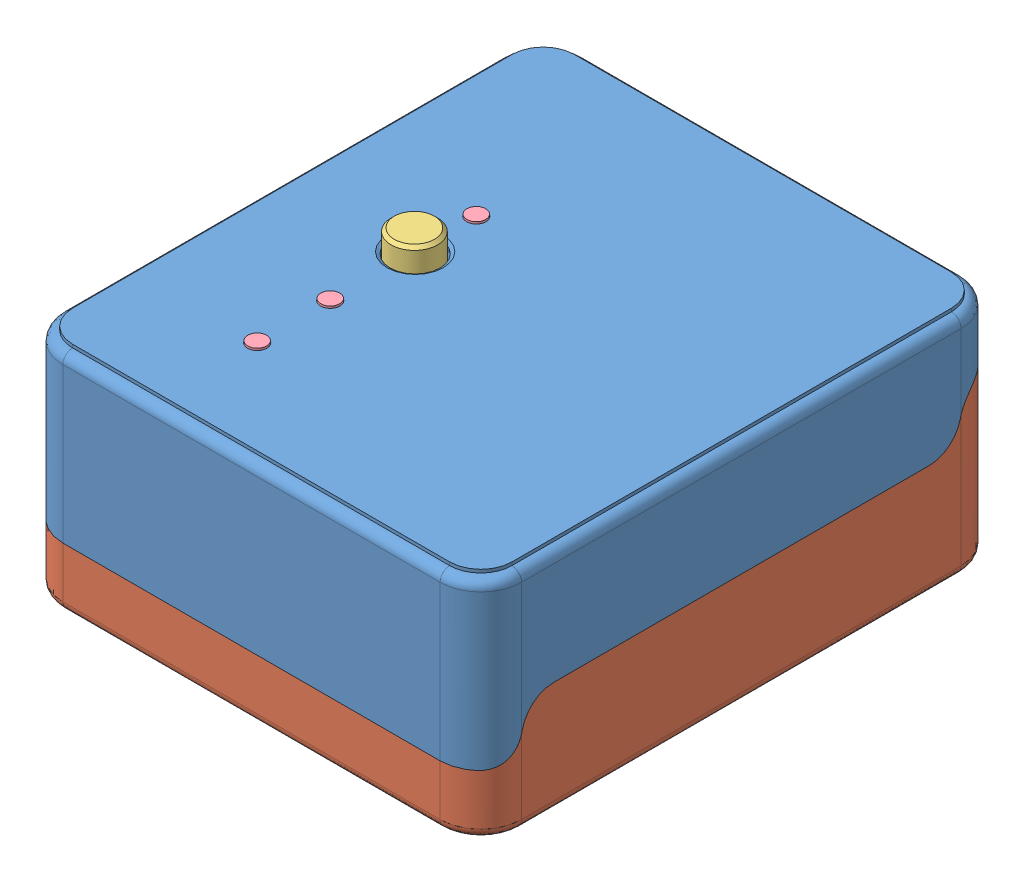
SolidWorks assembly Muscle Mouse v1_1, configuration Default. Lengths in mm.
Overall size (71.44 38.68 81.15).
62 component instances, 14 part files, 176 mates.
Components (placement in the parent):
- Muscle Mouse Board v1.1-1: Muscle Mouse Board v1.1 [Default] at (-18.1857 -3.7277 12.1289) size (55.43 1.85 75.95) (hidden)
- ArduinoMiniPro-1: ArduinoMiniPro [Default] at (-3.4501 0.5723 -8.9143) size (18.31 0.85 33) (hidden)
- BluSmiRF HID-1: BluSmiRF HID [Default] at (-16.9076 0.9474 31.4222) x (0 0 -1) z (1 0 0) size (16.15 3.53 42.04) (hidden)
- Muscle Sensor v3-1: Muscle Sensor v3 [Default] at (-33.1753 0.9474 -13.1715) size (25.4 6.61 28.3) (hidden)
- keystone-PN2479-1: keystone-PN2479 [Default] at (-25.1841 -16.2808 -8.533) x (1 0 0) z (0 0 -1) size (59.43 26.06 37.49) (hidden)
- keystone-PN2479-2: keystone-PN2479 [Default] at (-8.2546 -16.2808 33.121) x (-1 0 0) z (0 0 1) size (59.43 26.06 37.49) (hidden)
- HeaderPin-1: HeaderPin [Default] at (-36.6561 -1.3527 25.0722) x (1 0 0) z (0 0 -1) size (2.5 8.75 2.5) (hidden)
- HeaderPin-2: HeaderPin [Default] at (-36.6561 -1.3527 27.6122) x (1 0 0) z (0 0 -1) size (2.5 8.75 2.5) (hidden)
- HeaderPin-3: HeaderPin [Default] at (-36.6561 -1.3527 30.1522) x (1 0 0) z (0 0 -1) size (2.5 8.75 2.5) (hidden)
- HeaderPin-4: HeaderPin [Default] at (-36.6561 -1.3527 32.6922) x (1 0 0) z (0 0 -1) size (2.5 8.75 2.5) (hidden)
- HeaderPin-5: HeaderPin [Default] at (-36.6561 -1.3527 35.2322) x (1 0 0) z (0 0 -1) size (2.5 8.75 2.5) (hidden)
- HeaderPin-6: HeaderPin [Default] at (-36.6561 -1.3527 37.7722) x (1 0 0) z (0 0 -1) size (2.5 8.75 2.5) (hidden)
- HeaderPin-7: HeaderPin [Default] at (-44.2751 -1.3527 -2.0717) x (1 0 0) z (0 0 -1) size (2.5 8.75 2.5) (hidden)
- HeaderPin-8: HeaderPin [Default] at (-41.7351 -1.3527 -2.0717) x (1 0 0) z (0 0 -1) size (2.5 8.75 2.5) (hidden)
- HeaderPin-9: HeaderPin [Default] at (-39.1951 -1.3527 -2.0717) x (1 0 0) z (0 0 -1) size (2.5 8.75 2.5) (hidden)
- HeaderPin-10: HeaderPin [Default] at (-29.0351 -1.3527 -2.0717) x (1 0 0) z (0 0 -1) size (2.5 8.75 2.5) (hidden)
- HeaderPin-11: HeaderPin [Default] at (-10.8161 -1.3527 -24.1443) x (1 0 0) z (0 0 -1) size (2.5 8.75 2.5) (hidden)
- HeaderPin-12: HeaderPin [Default] at (-31.5751 -1.3527 -2.0717) x (1 0 0) z (0 0 -1) size (2.5 8.75 2.5) (hidden)
- HeaderPin-13: HeaderPin [Default] at (-10.8161 -1.3527 -1.2843) x (1 0 0) z (0 0 -1) size (2.5 8.75 2.5) (hidden)
- HeaderPin-14: HeaderPin [Default] at (-4.7201 -1.3527 6.3357) x (1 0 0) z (0 0 -1) size (2.5 8.75 2.5) (hidden)
- HeaderPin-15: HeaderPin [Default] at (-7.2601 -1.3527 6.3357) x (1 0 0) z (0 0 -1) size (2.5 8.75 2.5) (hidden)
- HeaderPin-16: HeaderPin [Default] at (-2.1801 -1.3527 6.3357) x (1 0 0) z (0 0 -1) size (2.5 8.75 2.5) (hidden)
- HeaderPin-17: HeaderPin [Default] at (3.9159 -1.3527 1.2557) x (1 0 0) z (0 0 -1) size (2.5 8.75 2.5) (hidden)
- HeaderPin-18: HeaderPin [Default] at (3.9159 -1.3527 -6.3643) x (1 0 0) z (0 0 -1) size (2.5 8.75 2.5) (hidden)
- HeaderPin-19: HeaderPin [Default] at (3.9159 -1.3527 -3.8243) x (1 0 0) z (0 0 -1) size (2.5 8.75 2.5) (hidden)
- HeaderPin-20: HeaderPin [Default] at (-10.8161 -1.3527 -8.9043) x (1 0 0) z (0 0 -1) size (2.5 8.75 2.5) (hidden)
- HeaderPin-21: HeaderPin [Default] at (-10.8161 -1.3527 -16.5243) x (1 0 0) z (0 0 -1) size (2.5 8.75 2.5) (hidden)
- HeaderPin-22: HeaderPin [Default] at (-10.8161 -1.3527 -11.4443) x (1 0 0) z (0 0 -1) size (2.5 8.75 2.5) (hidden)
- HeaderPin-23: HeaderPin [Default] at (-10.8161 -1.3527 -13.9843) x (1 0 0) z (0 0 -1) size (2.5 8.75 2.5) (hidden)
- HeaderPin-24: HeaderPin [Default] at (-10.8161 -1.3527 -6.3643) x (1 0 0) z (0 0 -1) size (2.5 8.75 2.5) (hidden)
- HeaderPin-25: HeaderPin [Default] at (-9.8001 -1.3527 6.3357) x (1 0 0) z (0 0 -1) size (2.5 8.75 2.5) (hidden)
- HeaderPin-26: HeaderPin [Default] at (-10.8161 -1.3527 -3.8243) x (1 0 0) z (0 0 -1) size (2.5 8.75 2.5) (hidden)
- HeaderPin-27: HeaderPin [Default] at (-10.8161 -1.3527 -21.6043) x (1 0 0) z (0 0 -1) size (2.5 8.75 2.5) (hidden)
- HeaderPin-28: HeaderPin [Default] at (3.9159 -1.3527 -1.2843) x (1 0 0) z (0 0 -1) size (2.5 8.75 2.5) (hidden)
- HeaderPin-29: HeaderPin [Default] at (-10.8161 -1.3527 1.2557) x (1 0 0) z (0 0 -1) size (2.5 8.75 2.5) (hidden)
- HeaderPin-30: HeaderPin [Default] at (3.9159 -1.3527 3.7957) x (1 0 0) z (0 0 -1) size (2.5 8.75 2.5) (hidden)
- HeaderPin-31: HeaderPin [Default] at (3.9159 -1.3527 -11.4443) x (1 0 0) z (0 0 -1) size (2.5 8.75 2.5) (hidden)
- HeaderPin-32: HeaderPin [Default] at (3.9159 -1.3527 -8.9043) x (1 0 0) z (0 0 -1) size (2.5 8.75 2.5) (hidden)
- HeaderPin-33: HeaderPin [Default] at (3.9159 -1.3527 -13.9843) x (1 0 0) z (0 0 -1) size (2.5 8.75 2.5) (hidden)
- HeaderPin-34: HeaderPin [Default] at (3.9159 -1.3527 -21.6043) x (1 0 0) z (0 0 -1) size (2.5 8.75 2.5) (hidden)
- HeaderPin-35: HeaderPin [Default] at (3.9159 -1.3527 -19.0643) x (1 0 0) z (0 0 -1) size (2.5 8.75 2.5) (hidden)
- HeaderPin-36: HeaderPin [Default] at (3.9159 -1.3527 -16.5243) x (1 0 0) z (0 0 -1) size (2.5 8.75 2.5) (hidden)
- HeaderPin-37: HeaderPin [Default] at (0.3599 -1.3527 6.3357) x (1 0 0) z (0 0 -1) size (2.5 8.75 2.5) (hidden)
- HeaderPin-38: HeaderPin [Default] at (-10.8161 -1.3527 3.7957) x (1 0 0) z (0 0 -1) size (2.5 8.75 2.5) (hidden)
- HeaderPin-39: HeaderPin [Default] at (2.8999 -1.3527 6.3357) x (1 0 0) z (0 0 -1) size (2.5 8.75 2.5) (hidden)
- HeaderPin-40: HeaderPin [Default] at (-10.8161 -1.3527 -19.0643) x (1 0 0) z (0 0 -1) size (2.5 8.75 2.5) (hidden)
- HeaderPin-41: HeaderPin [Default] at (3.9159 -1.3527 -24.1443) x (1 0 0) z (0 0 -1) size (2.5 8.75 2.5) (hidden)
- ClippedPin-1: ClippedPin [Default] at (-44.4402 -1.3527 -24.4618) x (0 0 -1) z (-1 0 0) size (2.5 5.25 2.5) (hidden)
- ClippedPin-2: ClippedPin [Default] at (2.4554 -1.3527 24.7801) x (0 0 -1) z (-1 0 0) size (2.5 5.25 2.5) (hidden)
- ClippedPin-3: ClippedPin [Default] at (2.43 -1.3527 38.0897) x (0 0 -1) z (-1 0 0) size (2.5 5.25 2.5) (hidden)
- ClippedPin-4: ClippedPin [Default] at (-21.8469 -1.3527 -24.4872) x (0 0 -1) z (-1 0 0) size (2.5 5.25 2.5) (hidden)
- PushbuttonBottom-1: PushbuttonBottom [Default] at (-31.9715 -2.2177 12.3106) x (0 0 -1) z (1 0 0) size (9.72 19.93 8.45) (hidden)
- EnclosureTop-1: EnclosureTop [Default] at (-16.7257 13.8198 12.1289) x (-1 0 0) z (0 0 1) size (71.44 26.6 81.15)
- EnclosureBottom-1: EnclosureBottom [Default] at (-16.7257 -21.1802 12.1289) size (71.44 25.43 81.15)
- ButtonCap-1: ButtonCap [Default] at (-31.9965 10.6798 12.0606) size (7.25 6.82 7.25)
- 11mmLightTube-1: 11mmLightTube [Default] at (-31.9053 3.3598 36.6289) size (3.75 11.25 3.75)
- 11mmLightTube-2: 11mmLightTube [Default] at (-31.9053 3.3598 25.2539) size (3.75 11.25 3.75)
- 11mmLightTube-3: 11mmLightTube [Default] at (-31.9053 3.3598 2.5089) size (3.75 11.25 3.75)
- 92010A126-2: 92010A126 [92010A126] at (13.2921 -19.1802 -8.1594) x (-0.055382 0 0.998465) z (0 -1 0) size (5.6 5.6 16.24) (hidden)
- 92010A126-4: 92010A126 [92010A126] at (13.2921 -19.1802 32.4171) x (1 0 0) z (0 -1 0) size (5.6 5.6 16.24) (hidden)
- 92010A126-8: 92010A126 [92010A126] at (-46.7434 -19.1884 12.1289) x (0.93096 0 0.36512) z (0 -1 0) size (5.6 5.6 16.24) (hidden)
- 92010A020-1: 92010A020 [92010A020] at (-16.6663 -6.003 43.1062) x (1 0 0) z (0 -1 0) size (4.7 4.7 10.19) (hidden)
Mates (geometry in assembly coordinates):
- Concentric1: concentric aligned: cylinder of Muscle Mouse Board v1.1-1 through (-36.6561 -4.6027 25.0722) axis (0 1 0) radius 0.508; cylinder of BluSmiRF HID-1 through (-36.6561 0.1473 25.0722) axis (0 1 0) radius 0.508
- Concentric2: concentric aligned: cylinder of Muscle Mouse Board v1.1-1 through (-36.6561 -4.6027 37.7722) axis (0 1 0) radius 0.508; cylinder of BluSmiRF HID-1 through (-36.6561 0.1473 37.7722) axis (0 1 0) radius 0.508
- Concentric3: concentric aligned: cylinder of Muscle Mouse Board v1.1-1 through (6.9512 -4.6027 -18.5182) axis (0 1 0) radius 0.508; cylinder of keystone-PN2479-1 through (6.9512 -11.9073 -18.5182) axis (0 1 0) radius 0.4064
- Concentric4: concentric aligned: cylinder of Muscle Mouse Board v1.1-1 through (6.9512 -4.6027 -5.8182) axis (0 1 0) radius 0.508; cylinder of keystone-PN2479-1 through (6.9512 -11.9073 -5.8182) axis (0 1 0) radius 0.4064
- Concentric5: concentric aligned: cylinder of Muscle Mouse Board v1.1-1 through (-40.3899 -4.6027 43.1062) axis (0 1 0) radius 0.508; cylinder of keystone-PN2479-2 through (-40.3899 -11.9073 43.1062) axis (0 1 0) radius 0.4064
- Concentric6: concentric aligned: cylinder of Muscle Mouse Board v1.1-1 through (-40.3899 -4.6027 30.4062) axis (0 1 0) radius 0.508; cylinder of keystone-PN2479-2 through (-40.3899 -11.9073 30.4062) axis (0 1 0) radius 0.4064
- Concentric7: concentric aligned: cylinder of Muscle Mouse Board v1.1-1 through (-44.2751 -4.6027 -2.0717) axis (0 1 0) radius 0.508; cylinder of Muscle Sensor v3-1 through (-44.2751 0.1473 -2.0717) axis (0 1 0) radius 0.635
- Concentric8: concentric aligned: cylinder of Muscle Mouse Board v1.1-1 through (-29.0351 -4.6027 -2.0717) axis (0 1 0) radius 0.508; cylinder of Muscle Sensor v3-1 through (-29.0351 0.1473 -2.0717) axis (0 1 0) radius 0.635
- Concentric9: concentric aligned: cylinder of Muscle Mouse Board v1.1-1 through (-36.6561 -4.6027 37.7722) axis (0 1 0) radius 0.508; cylinder of HeaderPin-6 through (-36.6561 -5.1027 37.7722) axis (0 1 0) radius 0.4953
- Coincident1: coincident anti-aligned: plane of Muscle Mouse Board v1.1-1 through (9.5293 -2.8527 50.1039) normal (0 1 0); plane of HeaderPin-6 through (-35.4061 -2.8527 36.5222) normal (0 -1 0)
- Coincident2: coincident anti-aligned: plane of BluSmiRF HID-1 through (4.1109 0.1473 23.345) normal (0 -1 0); plane of HeaderPin-6 through (-35.4061 0.1473 36.5222) normal (0 1 0)
- Parallel1: parallel aligned: plane of BluSmiRF HID-1 through (-37.9261 1.7475 39.4994) normal (-1 0 0); plane of HeaderPin-6 through (-37.9061 -2.8527 39.0222) normal (-1 0 0)
- Concentric10: concentric aligned: cylinder of Muscle Mouse Board v1.1-1 through (-36.6561 -4.6027 35.2322) axis (0 1 0) radius 0.508; cylinder of HeaderPin-5 through (-36.6561 -5.1027 35.2322) axis (0 1 0) radius 0.4953
- Concentric11: concentric aligned: cylinder of Muscle Mouse Board v1.1-1 through (-36.6561 -4.6027 32.6922) axis (0 1 0) radius 0.508; cylinder of HeaderPin-4 through (-36.6561 -5.1027 32.6922) axis (0 1 0) radius 0.4953
- Concentric12: concentric aligned: cylinder of Muscle Mouse Board v1.1-1 through (-36.6561 -4.6027 30.1522) axis (0 1 0) radius 0.508; cylinder of HeaderPin-3 through (-36.6561 -5.1027 30.1522) axis (0 1 0) radius 0.4953
- Concentric13: concentric aligned: cylinder of Muscle Mouse Board v1.1-1 through (-36.6561 -4.6027 27.6122) axis (0 1 0) radius 0.508; cylinder of HeaderPin-2 through (-36.6561 -5.1027 27.6122) axis (0 1 0) radius 0.4953
- Concentric14: concentric aligned: cylinder of Muscle Mouse Board v1.1-1 through (-36.6561 -4.6027 25.0722) axis (0 1 0) radius 0.508; cylinder of HeaderPin-1 through (-36.6561 -5.1027 25.0722) axis (0 1 0) radius 0.4953
- Parallel2: parallel aligned: plane of BluSmiRF HID-1 through (-37.9261 1.7475 39.4994) normal (-1 0 0); plane of HeaderPin-5 through (-37.9061 -2.8527 36.4822) normal (-1 0 0)
- Parallel4: parallel aligned: plane of BluSmiRF HID-1 through (-37.9261 1.7475 39.4994) normal (-1 0 0); plane of HeaderPin-4 through (-37.9061 -2.8527 33.9422) normal (-1 0 0)
- Parallel5: parallel aligned: plane of BluSmiRF HID-1 through (-37.9261 1.7475 39.4994) normal (-1 0 0); plane of HeaderPin-3 through (-37.9061 -2.8527 31.4022) normal (-1 0 0)
- Parallel6: parallel aligned: plane of BluSmiRF HID-1 through (-37.9261 1.7475 39.4994) normal (-1 0 0); plane of HeaderPin-2 through (-37.9061 -2.8527 28.8622) normal (-1 0 0)
- Parallel7: parallel aligned: plane of BluSmiRF HID-1 through (-37.9261 1.7475 39.4994) normal (-1 0 0); plane of HeaderPin-1 through (-37.9061 -2.8527 26.3222) normal (-1 0 0)
- Coincident10: coincident anti-aligned: plane of Muscle Mouse Board v1.1-1 through (9.5293 -2.8527 50.1039) normal (0 1 0); plane of HeaderPin-5 through (-35.4061 -2.8527 33.9822) normal (0 -1 0)
- Coincident11: coincident anti-aligned: plane of Muscle Mouse Board v1.1-1 through (9.5293 -2.8527 50.1039) normal (0 1 0); plane of HeaderPin-4 through (-35.4061 -2.8527 31.4422) normal (0 -1 0)
- Coincident12: coincident anti-aligned: plane of Muscle Mouse Board v1.1-1 through (9.5293 -2.8527 50.1039) normal (0 1 0); plane of HeaderPin-3 through (-35.4061 -2.8527 28.9022) normal (0 -1 0)
- Coincident13: coincident anti-aligned: plane of Muscle Mouse Board v1.1-1 through (9.5293 -2.8527 50.1039) normal (0 1 0); plane of HeaderPin-2 through (-35.4061 -2.8527 26.3622) normal (0 -1 0)
- Coincident14: coincident anti-aligned: plane of Muscle Mouse Board v1.1-1 through (9.5293 -2.8527 50.1039) normal (0 1 0); plane of HeaderPin-1 through (-35.4061 -2.8527 23.8222) normal (0 -1 0)
- Concentric15: concentric aligned: cylinder of Muscle Mouse Board v1.1-1 through (-44.2751 -4.6027 -2.0717) axis (0 1 0) radius 0.508; cylinder of HeaderPin-7 through (-44.2751 -5.1027 -2.0717) axis (0 1 0) radius 0.4953
- Concentric16: concentric aligned: cylinder of Muscle Mouse Board v1.1-1 through (-41.7351 -4.6027 -2.0717) axis (0 1 0) radius 0.508; cylinder of HeaderPin-8 through (-41.7351 -5.1027 -2.0717) axis (0 1 0) radius 0.4953
- Concentric17: concentric aligned: cylinder of Muscle Mouse Board v1.1-1 through (-39.1951 -4.6027 -2.0717) axis (0 1 0) radius 0.508; cylinder of HeaderPin-9 through (-39.1951 -5.1027 -2.0717) axis (0 1 0) radius 0.4953
- Concentric18: concentric aligned: cylinder of Muscle Mouse Board v1.1-1 through (-31.5751 -4.6027 -2.0717) axis (0 1 0) radius 0.508; cylinder of HeaderPin-12 through (-31.5751 -5.1027 -2.0717) axis (0 1 0) radius 0.4953
- Concentric19: concentric aligned: cylinder of Muscle Mouse Board v1.1-1 through (-29.0351 -4.6027 -2.0717) axis (0 1 0) radius 0.508; cylinder of HeaderPin-10 through (-29.0351 -5.1027 -2.0717) axis (0 1 0) radius 0.4953
- Coincident15: coincident anti-aligned: plane of Muscle Mouse Board v1.1-1 through (9.5293 -2.8527 50.1039) normal (0 1 0); plane of HeaderPin-7 through (-43.0251 -2.8527 -3.3217) normal (0 -1 0)
- Coincident16: coincident anti-aligned: plane of Muscle Mouse Board v1.1-1 through (9.5293 -2.8527 50.1039) normal (0 1 0); plane of HeaderPin-8 through (-40.4851 -2.8527 -3.3217) normal (0 -1 0)
- Coincident17: coincident anti-aligned: plane of Muscle Mouse Board v1.1-1 through (9.5293 -2.8527 50.1039) normal (0 1 0); plane of HeaderPin-9 through (-37.9451 -2.8527 -3.3217) normal (0 -1 0)
- Coincident18: coincident anti-aligned: plane of Muscle Mouse Board v1.1-1 through (9.5293 -2.8527 50.1039) normal (0 1 0); plane of HeaderPin-12 through (-30.3251 -2.8527 -3.3217) normal (0 -1 0)
- Coincident19: coincident anti-aligned: plane of Muscle Mouse Board v1.1-1 through (9.5293 -2.8527 50.1039) normal (0 1 0); plane of HeaderPin-10 through (-27.7851 -2.8527 -3.3217) normal (0 -1 0)
- Parallel8: parallel aligned: plane of Muscle Mouse Board v1.1-1 through (-45.9007 -2.8527 -25.8461) normal (0 0 -1); plane of HeaderPin-7 through (-45.5251 -2.8527 -3.3217) normal (0 0 -1)
- Parallel9: parallel aligned: plane of Muscle Mouse Board v1.1-1 through (-45.9007 -2.8527 -25.8461) normal (0 0 -1); plane of HeaderPin-8 through (-42.9851 -2.8527 -3.3217) normal (0 0 -1)
- Parallel10: parallel aligned: plane of Muscle Mouse Board v1.1-1 through (-45.9007 -2.8527 -25.8461) normal (0 0 -1); plane of HeaderPin-9 through (-40.4451 -2.8527 -3.3217) normal (0 0 -1)
- Parallel11: parallel aligned: plane of Muscle Mouse Board v1.1-1 through (-45.9007 -2.8527 -25.8461) normal (0 0 -1); plane of HeaderPin-12 through (-32.8251 -2.8527 -3.3217) normal (0 0 -1)
- Parallel12: parallel aligned: plane of Muscle Mouse Board v1.1-1 through (-45.9007 -2.8527 -25.8461) normal (0 0 -1); plane of HeaderPin-10 through (-30.2851 -2.8527 -3.3217) normal (0 0 -1)
- Coincident25: coincident anti-aligned: plane of Muscle Sensor v3-1 through (-45.8753 0.1473 -0.4715) normal (0 -1 0); plane of HeaderPin-7 through (-43.0251 0.1473 -3.3217) normal (0 1 0)
- Concentric20: concentric anti-aligned: cylinder of Muscle Mouse Board v1.1-1 through (-10.8161 -4.6027 -24.1443) axis (0 1 0) radius 0.508; cylinder of ArduinoMiniPro-1 through (-10.8161 0.9973 -24.1443) axis (0 -1 0) radius 0.508
- Concentric22: concentric anti-aligned: cylinder of Muscle Mouse Board v1.1-1 through (3.9159 -4.6027 3.7957) axis (0 1 0) radius 0.508; cylinder of ArduinoMiniPro-1 through (3.9159 0.9973 3.7957) axis (0 -1 0) radius 0.508
- Concentric23: concentric aligned: cylinder of Muscle Mouse Board v1.1-1 through (3.9159 -4.6027 -24.1443) axis (0 1 0) radius 0.508; cylinder of HeaderPin-41 through (3.9159 -5.1027 -24.1443) axis (0 1 0) radius 0.4953
- Concentric24: concentric aligned: cylinder of Muscle Mouse Board v1.1-1 through (3.9159 -4.6027 -21.6043) axis (0 1 0) radius 0.508; cylinder of HeaderPin-34 through (3.9159 -5.1027 -21.6043) axis (0 1 0) radius 0.4953
- Concentric25: concentric aligned: cylinder of Muscle Mouse Board v1.1-1 through (3.9159 -4.6027 -19.0643) axis (0 1 0) radius 0.508; cylinder of HeaderPin-35 through (3.9159 -5.1027 -19.0643) axis (0 1 0) radius 0.4953
- Concentric26: concentric aligned: cylinder of Muscle Mouse Board v1.1-1 through (3.9159 -4.6027 -16.5243) axis (0 1 0) radius 0.508; cylinder of HeaderPin-36 through (3.9159 -5.1027 -16.5243) axis (0 1 0) radius 0.4953
- Concentric27: concentric aligned: cylinder of Muscle Mouse Board v1.1-1 through (3.9159 -4.6027 -13.9843) axis (0 1 0) radius 0.508; cylinder of HeaderPin-33 through (3.9159 -5.1027 -13.9843) axis (0 1 0) radius 0.4953
- Concentric28: concentric aligned: cylinder of Muscle Mouse Board v1.1-1 through (3.9159 -4.6027 -11.4443) axis (0 1 0) radius 0.508; cylinder of HeaderPin-31 through (3.9159 -5.1027 -11.4443) axis (0 1 0) radius 0.4953
- Concentric30: concentric aligned: cylinder of Muscle Mouse Board v1.1-1 through (3.9159 -4.6027 -8.9043) axis (0 1 0) radius 0.508; cylinder of HeaderPin-32 through (3.9159 -5.1027 -8.9043) axis (0 1 0) radius 0.4953
- Concentric31: concentric aligned: cylinder of Muscle Mouse Board v1.1-1 through (3.9159 -4.6027 -6.3643) axis (0 1 0) radius 0.508; cylinder of HeaderPin-18 through (3.9159 -5.1027 -6.3643) axis (0 1 0) radius 0.4953
- Concentric32: concentric aligned: cylinder of Muscle Mouse Board v1.1-1 through (3.9159 -4.6027 3.7957) axis (0 1 0) radius 0.508; cylinder of HeaderPin-30 through (3.9159 -5.1027 3.7957) axis (0 1 0) radius 0.4953
- Concentric33: concentric aligned: cylinder of Muscle Mouse Board v1.1-1 through (3.9159 -4.6027 1.2557) axis (0 1 0) radius 0.508; cylinder of HeaderPin-17 through (3.9159 -5.1027 1.2557) axis (0 1 0) radius 0.4953
- Concentric34: concentric aligned: cylinder of Muscle Mouse Board v1.1-1 through (3.9159 -4.6027 -1.2843) axis (0 1 0) radius 0.508; cylinder of HeaderPin-28 through (3.9159 -5.1027 -1.2843) axis (0 1 0) radius 0.4953
- Concentric35: concentric aligned: cylinder of Muscle Mouse Board v1.1-1 through (3.9159 -4.6027 -3.8243) axis (0 1 0) radius 0.508; cylinder of HeaderPin-19 through (3.9159 -5.1027 -3.8243) axis (0 1 0) radius 0.4953
- Concentric36: concentric aligned: cylinder of Muscle Mouse Board v1.1-1 through (2.8999 -4.6027 6.3357) axis (0 1 0) radius 0.508; cylinder of HeaderPin-39 through (2.8999 -5.1027 6.3357) axis (0 1 0) radius 0.4953
- Parallel13: parallel aligned: plane of Muscle Mouse Board v1.1-1 through (9.5293 -2.8527 -25.8461) normal (1 0 0); plane of HeaderPin-30 through (5.1659 -2.8527 5.0457) normal (1 0 0)
- Parallel14: parallel aligned: plane of Muscle Mouse Board v1.1-1 through (9.5293 -2.8527 -25.8461) normal (1 0 0); plane of HeaderPin-17 through (5.1659 -2.8527 2.5057) normal (1 0 0)
- Parallel15: parallel aligned: plane of Muscle Mouse Board v1.1-1 through (9.5293 -2.8527 -25.8461) normal (1 0 0); plane of HeaderPin-28 through (5.1659 -2.8527 -0.0343) normal (1 0 0)
- Parallel16: parallel aligned: plane of Muscle Mouse Board v1.1-1 through (9.5293 -2.8527 -25.8461) normal (1 0 0); plane of HeaderPin-19 through (5.1659 -2.8527 -2.5743) normal (1 0 0)
- Parallel17: parallel aligned: plane of Muscle Mouse Board v1.1-1 through (9.5293 -2.8527 -25.8461) normal (1 0 0); plane of HeaderPin-18 through (5.1659 -2.8527 -5.1143) normal (1 0 0)
- Parallel18: parallel aligned: plane of Muscle Mouse Board v1.1-1 through (9.5293 -2.8527 -25.8461) normal (1 0 0); plane of HeaderPin-32 through (5.1659 -2.8527 -7.6543) normal (1 0 0)
- Parallel19: parallel aligned: plane of Muscle Mouse Board v1.1-1 through (9.5293 -2.8527 -25.8461) normal (1 0 0); plane of HeaderPin-31 through (5.1659 -2.8527 -10.1943) normal (1 0 0)
- Parallel20: parallel aligned: plane of Muscle Mouse Board v1.1-1 through (9.5293 -2.8527 -25.8461) normal (1 0 0); plane of HeaderPin-33 through (5.1659 -2.8527 -12.7343) normal (1 0 0)
- Parallel21: parallel aligned: plane of Muscle Mouse Board v1.1-1 through (9.5293 -2.8527 -25.8461) normal (1 0 0); plane of HeaderPin-36 through (5.1659 -2.8527 -15.2743) normal (1 0 0)
- Parallel22: parallel aligned: plane of Muscle Mouse Board v1.1-1 through (9.5293 -2.8527 -25.8461) normal (1 0 0); plane of HeaderPin-35 through (5.1659 -2.8527 -17.8143) normal (1 0 0)
- Parallel23: parallel aligned: plane of Muscle Mouse Board v1.1-1 through (9.5293 -2.8527 -25.8461) normal (1 0 0); plane of HeaderPin-34 through (5.1659 -2.8527 -20.3543) normal (1 0 0)
- Parallel24: parallel aligned: plane of Muscle Mouse Board v1.1-1 through (9.5293 -2.8527 -25.8461) normal (1 0 0); plane of HeaderPin-41 through (5.1659 -2.8527 -22.8943) normal (1 0 0)
- Coincident38: coincident anti-aligned: plane of Muscle Mouse Board v1.1-1 through (9.5293 -2.8527 50.1039) normal (0 1 0); plane of HeaderPin-39 through (4.1499 -2.8527 5.0857) normal (0 -1 0)
- Coincident39: coincident anti-aligned: plane of Muscle Mouse Board v1.1-1 through (9.5293 -2.8527 50.1039) normal (0 1 0); plane of HeaderPin-30 through (5.1659 -2.8527 2.5457) normal (0 -1 0)
- Coincident40: coincident anti-aligned: plane of Muscle Mouse Board v1.1-1 through (9.5293 -2.8527 50.1039) normal (0 1 0); plane of HeaderPin-28 through (5.1659 -2.8527 -2.5343) normal (0 -1 0)
- Coincident41: coincident anti-aligned: plane of Muscle Mouse Board v1.1-1 through (9.5293 -2.8527 50.1039) normal (0 1 0); plane of HeaderPin-17 through (5.1659 -2.8527 0.0057) normal (0 -1 0)
- Coincident42: coincident anti-aligned: plane of Muscle Mouse Board v1.1-1 through (9.5293 -2.8527 50.1039) normal (0 1 0); plane of HeaderPin-19 through (5.1659 -2.8527 -5.0743) normal (0 -1 0)
- Coincident43: coincident anti-aligned: plane of Muscle Mouse Board v1.1-1 through (9.5293 -2.8527 50.1039) normal (0 1 0); plane of HeaderPin-18 through (5.1659 -2.8527 -7.6143) normal (0 -1 0)
- Coincident44: coincident anti-aligned: plane of Muscle Mouse Board v1.1-1 through (9.5293 -2.8527 50.1039) normal (0 1 0); plane of HeaderPin-32 through (5.1659 -2.8527 -10.1543) normal (0 -1 0)
- Coincident45: coincident anti-aligned: plane of Muscle Mouse Board v1.1-1 through (9.5293 -2.8527 50.1039) normal (0 1 0); plane of HeaderPin-31 through (5.1659 -2.8527 -12.6943) normal (0 -1 0)
- Coincident46: coincident anti-aligned: plane of Muscle Mouse Board v1.1-1 through (9.5293 -2.8527 50.1039) normal (0 1 0); plane of HeaderPin-33 through (5.1659 -2.8527 -15.2343) normal (0 -1 0)
- Coincident47: coincident anti-aligned: plane of Muscle Mouse Board v1.1-1 through (9.5293 -2.8527 50.1039) normal (0 1 0); plane of HeaderPin-36 through (5.1659 -2.8527 -17.7743) normal (0 -1 0)
- Coincident48: coincident anti-aligned: plane of Muscle Mouse Board v1.1-1 through (9.5293 -2.8527 50.1039) normal (0 1 0); plane of HeaderPin-35 through (5.1659 -2.8527 -20.3143) normal (0 -1 0)
- Coincident49: coincident anti-aligned: plane of Muscle Mouse Board v1.1-1 through (9.5293 -2.8527 50.1039) normal (0 1 0); plane of HeaderPin-34 through (5.1659 -2.8527 -22.8543) normal (0 -1 0)
- Coincident50: coincident anti-aligned: plane of Muscle Mouse Board v1.1-1 through (9.5293 -2.8527 50.1039) normal (0 1 0); plane of HeaderPin-41 through (5.1659 -2.8527 -25.3943) normal (0 -1 0)
- Concentric37: concentric aligned: cylinder of Muscle Mouse Board v1.1-1 through (0.3599 -4.6027 6.3357) axis (0 1 0) radius 0.508; cylinder of HeaderPin-37 through (0.3599 -5.1027 6.3357) axis (0 1 0) radius 0.4953
- Concentric39: concentric aligned: cylinder of Muscle Mouse Board v1.1-1 through (-4.7201 -4.6027 6.3357) axis (0 1 0) radius 0.508; cylinder of HeaderPin-14 through (-4.7201 -5.1027 6.3357) axis (0 1 0) radius 0.4953
- Concentric40: concentric aligned: cylinder of Muscle Mouse Board v1.1-1 through (-2.1801 -4.6027 6.3357) axis (0 1 0) radius 0.508; cylinder of HeaderPin-16 through (-2.1801 -5.1027 6.3357) axis (0 1 0) radius 0.4953
- Concentric41: concentric aligned: cylinder of Muscle Mouse Board v1.1-1 through (-7.2601 -4.6027 6.3357) axis (0 1 0) radius 0.508; cylinder of HeaderPin-15 through (-7.2601 -5.1027 6.3357) axis (0 1 0) radius 0.4953
- Concentric42: concentric aligned: cylinder of Muscle Mouse Board v1.1-1 through (-9.8001 -4.6027 6.3357) axis (0 1 0) radius 0.508; cylinder of HeaderPin-25 through (-9.8001 -5.1027 6.3357) axis (0 1 0) radius 0.4953
- Parallel25: parallel aligned: plane of Muscle Mouse Board v1.1-1 through (9.5293 -2.8527 50.1039) normal (0 0 1); plane of HeaderPin-25 through (-11.0501 -2.8527 7.5857) normal (0 0 1)
- Parallel26: parallel aligned: plane of Muscle Mouse Board v1.1-1 through (9.5293 -2.8527 50.1039) normal (0 0 1); plane of HeaderPin-15 through (-8.5101 -2.8527 7.5857) normal (0 0 1)
- Parallel27: parallel aligned: plane of Muscle Mouse Board v1.1-1 through (9.5293 -2.8527 50.1039) normal (0 0 1); plane of HeaderPin-14 through (-5.9701 -2.8527 7.5857) normal (0 0 1)
- Parallel28: parallel aligned: plane of Muscle Mouse Board v1.1-1 through (9.5293 -2.8527 50.1039) normal (0 0 1); plane of HeaderPin-16 through (-3.4301 -2.8527 7.5857) normal (0 0 1)
- Parallel29: parallel aligned: plane of Muscle Mouse Board v1.1-1 through (9.5293 -2.8527 50.1039) normal (0 0 1); plane of HeaderPin-38 through (-12.0661 -2.8527 5.0457) normal (0 0 1)
- Coincident56: coincident anti-aligned: plane of Muscle Mouse Board v1.1-1 through (9.5293 -2.8527 50.1039) normal (0 1 0); plane of HeaderPin-37 through (1.6099 -2.8527 5.0857) normal (0 -1 0)
- Coincident57: coincident anti-aligned: plane of Muscle Mouse Board v1.1-1 through (9.5293 -2.8527 50.1039) normal (0 1 0); plane of HeaderPin-16 through (-0.9301 -2.8527 5.0857) normal (0 -1 0)
- Coincident58: coincident anti-aligned: plane of Muscle Mouse Board v1.1-1 through (9.5293 -2.8527 50.1039) normal (0 1 0); plane of HeaderPin-14 through (-3.4701 -2.8527 5.0857) normal (0 -1 0)
- Coincident59: coincident anti-aligned: plane of Muscle Mouse Board v1.1-1 through (9.5293 -2.8527 50.1039) normal (0 1 0); plane of HeaderPin-25 through (-8.5501 -2.8527 5.0857) normal (0 -1 0)
- Coincident60: coincident anti-aligned: plane of Muscle Mouse Board v1.1-1 through (9.5293 -2.8527 50.1039) normal (0 1 0); plane of HeaderPin-15 through (-6.0101 -2.8527 5.0857) normal (0 -1 0)
- Concentric43: concentric aligned: cylinder of Muscle Mouse Board v1.1-1 through (-10.8161 -4.6027 3.7957) axis (0 1 0) radius 0.508; cylinder of HeaderPin-38 through (-10.8161 -5.1027 3.7957) axis (0 1 0) radius 0.4953
- Concentric44: concentric aligned: cylinder of HeaderPin-29 through (-10.8161 -5.1027 1.2557) axis (0 1 0) radius 0.4953; cylinder of Muscle Mouse Board v1.1-1 through (-10.8161 -4.6027 1.2557) axis (0 1 0) radius 0.508
- Concentric45: concentric aligned: cylinder of Muscle Mouse Board v1.1-1 through (-10.8161 -4.6027 -1.2843) axis (0 1 0) radius 0.508; cylinder of HeaderPin-13 through (-10.8161 -5.1027 -1.2843) axis (0 1 0) radius 0.4953
- Concentric46: concentric aligned: cylinder of Muscle Mouse Board v1.1-1 through (-10.8161 -4.6027 -3.8243) axis (0 1 0) radius 0.508; cylinder of HeaderPin-26 through (-10.8161 -5.1027 -3.8243) axis (0 1 0) radius 0.4953
- Concentric47: concentric aligned: cylinder of Muscle Mouse Board v1.1-1 through (-10.8161 -4.6027 -6.3643) axis (0 1 0) radius 0.508; cylinder of HeaderPin-24 through (-10.8161 -5.1027 -6.3643) axis (0 1 0) radius 0.4953
- Concentric48: concentric aligned: cylinder of Muscle Mouse Board v1.1-1 through (-10.8161 -4.6027 -8.9043) axis (0 1 0) radius 0.508; cylinder of HeaderPin-20 through (-10.8161 -5.1027 -8.9043) axis (0 1 0) radius 0.4953
- Concentric49: concentric aligned: cylinder of Muscle Mouse Board v1.1-1 through (-10.8161 -4.6027 -24.1443) axis (0 1 0) radius 0.508; cylinder of HeaderPin-11 through (-10.8161 -5.1027 -24.1443) axis (0 1 0) radius 0.4953
- Concentric50: concentric aligned: cylinder of Muscle Mouse Board v1.1-1 through (-10.8161 -4.6027 -21.6043) axis (0 1 0) radius 0.508; cylinder of HeaderPin-27 through (-10.8161 -5.1027 -21.6043) axis (0 1 0) radius 0.4953
- Concentric51: concentric aligned: cylinder of Muscle Mouse Board v1.1-1 through (-10.8161 -4.6027 -19.0643) axis (0 1 0) radius 0.508; cylinder of HeaderPin-40 through (-10.8161 -5.1027 -19.0643) axis (0 1 0) radius 0.4953
- Concentric52: concentric aligned: cylinder of Muscle Mouse Board v1.1-1 through (-10.8161 -4.6027 -16.5243) axis (0 1 0) radius 0.508; cylinder of HeaderPin-21 through (-10.8161 -5.1027 -16.5243) axis (0 1 0) radius 0.4953
- Concentric53: concentric aligned: cylinder of Muscle Mouse Board v1.1-1 through (-10.8161 -4.6027 -11.4443) axis (0 1 0) radius 0.508; cylinder of HeaderPin-22 through (-10.8161 -5.1027 -11.4443) axis (0 1 0) radius 0.4953
- Concentric54: concentric aligned: cylinder of Muscle Mouse Board v1.1-1 through (-10.8161 -4.6027 -13.9843) axis (0 1 0) radius 0.508; cylinder of HeaderPin-23 through (-10.8161 -5.1027 -13.9843) axis (0 1 0) radius 0.4953
- Parallel30: parallel aligned: plane of Muscle Mouse Board v1.1-1 through (-45.9007 -2.8527 1.0539) normal (-1 0 0); plane of HeaderPin-11 through (-12.0661 -2.8527 -22.8943) normal (-1 0 0)
- Parallel31: parallel aligned: plane of Muscle Mouse Board v1.1-1 through (-45.9007 -2.8527 1.0539) normal (-1 0 0); plane of HeaderPin-27 through (-12.0661 -2.8527 -20.3543) normal (-1 0 0)
- Parallel32: parallel aligned: plane of Muscle Mouse Board v1.1-1 through (-45.9007 -2.8527 1.0539) normal (-1 0 0); plane of HeaderPin-40 through (-12.0661 -2.8527 -17.8143) normal (-1 0 0)
- Parallel33: parallel aligned: plane of Muscle Mouse Board v1.1-1 through (-45.9007 -2.8527 1.0539) normal (-1 0 0); plane of HeaderPin-21 through (-12.0661 -2.8527 -15.2743) normal (-1 0 0)
- Parallel34: parallel aligned: plane of Muscle Mouse Board v1.1-1 through (-45.9007 -2.8527 1.0539) normal (-1 0 0); plane of HeaderPin-23 through (-12.0661 -2.8527 -12.7343) normal (-1 0 0)
- Parallel35: parallel aligned: plane of Muscle Mouse Board v1.1-1 through (-45.9007 -2.8527 1.0539) normal (-1 0 0); plane of HeaderPin-22 through (-12.0661 -2.8527 -10.1943) normal (-1 0 0)
- Parallel36: parallel aligned: plane of Muscle Mouse Board v1.1-1 through (-45.9007 -2.8527 1.0539) normal (-1 0 0); plane of HeaderPin-20 through (-12.0661 -2.8527 -7.6543) normal (-1 0 0)
- Parallel37: parallel aligned: plane of Muscle Mouse Board v1.1-1 through (-45.9007 -2.8527 1.0539) normal (-1 0 0); plane of HeaderPin-24 through (-12.0661 -2.8527 -5.1143) normal (-1 0 0)
- Parallel38: parallel aligned: plane of Muscle Mouse Board v1.1-1 through (-45.9007 -2.8527 1.0539) normal (-1 0 0); plane of HeaderPin-26 through (-12.0661 -2.8527 -2.5743) normal (-1 0 0)
- Parallel39: parallel aligned: plane of Muscle Mouse Board v1.1-1 through (-45.9007 -2.8527 1.0539) normal (-1 0 0); plane of HeaderPin-13 through (-12.0661 -2.8527 -0.0343) normal (-1 0 0)
- Parallel40: parallel aligned: plane of Muscle Mouse Board v1.1-1 through (-45.9007 -2.8527 1.0539) normal (-1 0 0); plane of HeaderPin-29 through (-12.0661 -2.8527 2.5057) normal (-1 0 0)
- Parallel41: parallel aligned: plane of Muscle Mouse Board v1.1-1 through (-45.9007 -2.8527 1.0539) normal (-1 0 0); plane of HeaderPin-38 through (-12.0661 -2.8527 5.0457) normal (-1 0 0)
- Coincident73: coincident anti-aligned: plane of Muscle Mouse Board v1.1-1 through (9.5293 -2.8527 50.1039) normal (0 1 0); plane of HeaderPin-11 through (-9.5661 -2.8527 -25.3943) normal (0 -1 0)
- Coincident74: coincident anti-aligned: plane of Muscle Mouse Board v1.1-1 through (9.5293 -2.8527 50.1039) normal (0 1 0); plane of HeaderPin-27 through (-9.5661 -2.8527 -22.8543) normal (0 -1 0)
- Coincident75: coincident anti-aligned: plane of Muscle Mouse Board v1.1-1 through (9.5293 -2.8527 50.1039) normal (0 1 0); plane of HeaderPin-40 through (-9.5661 -2.8527 -20.3143) normal (0 -1 0)
- Coincident76: coincident anti-aligned: plane of Muscle Mouse Board v1.1-1 through (9.5293 -2.8527 50.1039) normal (0 1 0); plane of HeaderPin-21 through (-9.5661 -2.8527 -17.7743) normal (0 -1 0)
- Coincident77: coincident anti-aligned: plane of Muscle Mouse Board v1.1-1 through (9.5293 -2.8527 50.1039) normal (0 1 0); plane of HeaderPin-23 through (-9.5661 -2.8527 -15.2343) normal (0 -1 0)
- Coincident78: coincident anti-aligned: plane of Muscle Mouse Board v1.1-1 through (9.5293 -2.8527 50.1039) normal (0 1 0); plane of HeaderPin-22 through (-9.5661 -2.8527 -12.6943) normal (0 -1 0)
- Coincident79: coincident anti-aligned: plane of Muscle Mouse Board v1.1-1 through (9.5293 -2.8527 50.1039) normal (0 1 0); plane of HeaderPin-20 through (-9.5661 -2.8527 -10.1543) normal (0 -1 0)
- Coincident80: coincident anti-aligned: plane of Muscle Mouse Board v1.1-1 through (9.5293 -2.8527 50.1039) normal (0 1 0); plane of HeaderPin-24 through (-9.5661 -2.8527 -7.6143) normal (0 -1 0)
- Coincident81: coincident anti-aligned: plane of Muscle Mouse Board v1.1-1 through (9.5293 -2.8527 50.1039) normal (0 1 0); plane of HeaderPin-26 through (-9.5661 -2.8527 -5.0743) normal (0 -1 0)
- Coincident82: coincident anti-aligned: plane of Muscle Mouse Board v1.1-1 through (9.5293 -2.8527 50.1039) normal (0 1 0); plane of HeaderPin-38 through (-9.5661 -2.8527 2.5457) normal (0 -1 0)
- Coincident83: coincident anti-aligned: plane of Muscle Mouse Board v1.1-1 through (9.5293 -2.8527 50.1039) normal (0 1 0); plane of HeaderPin-13 through (-9.5661 -2.8527 -2.5343) normal (0 -1 0)
- Coincident84: coincident anti-aligned: plane of Muscle Mouse Board v1.1-1 through (9.5293 -2.8527 50.1039) normal (0 1 0); plane of HeaderPin-29 through (-9.5661 -2.8527 0.0057) normal (0 -1 0)
- Coincident85: coincident anti-aligned: plane of ArduinoMiniPro-1 through (5.7066 0.1473 7.5857) normal (0 -1 0); plane of HeaderPin-11 through (-9.5661 0.1473 -25.3943) normal (0 1 0)
- Concentric55: concentric aligned: cylinder of Muscle Mouse Board v1.1-1 through (-44.4402 -4.6027 -24.4618) axis (0 1 0) radius 0.508; cylinder of ClippedPin-1 through (-44.4402 -5.1027 -24.4618) axis (0 1 0) radius 0.4953
- Concentric56: concentric aligned: cylinder of Muscle Mouse Board v1.1-1 through (-21.8469 -4.6027 -24.4872) axis (0 1 0) radius 0.508; cylinder of ClippedPin-4 through (-21.8469 -5.1027 -24.4872) axis (0 1 0) radius 0.4953
- Concentric57: concentric aligned: cylinder of Muscle Mouse Board v1.1-1 through (2.43 -4.6027 38.0897) axis (0 1 0) radius 0.508; cylinder of ClippedPin-3 through (2.43 -5.1027 38.0897) axis (0 1 0) radius 0.4953
- Concentric58: concentric aligned: cylinder of Muscle Mouse Board v1.1-1 through (2.4554 -4.6027 24.7801) axis (0 1 0) radius 0.508; cylinder of ClippedPin-2 through (2.4554 -5.1027 24.7801) axis (0 1 0) radius 0.4953
- Coincident86: coincident anti-aligned: plane of Muscle Mouse Board v1.1-1 through (9.5293 -2.8527 50.1039) normal (0 1 0); plane of ClippedPin-1 through (-45.6902 -2.8527 -25.7118) normal (0 -1 0)
- Coincident87: coincident anti-aligned: plane of Muscle Mouse Board v1.1-1 through (9.5293 -2.8527 50.1039) normal (0 1 0); plane of ClippedPin-4 through (-23.0969 -2.8527 -25.7372) normal (0 -1 0)
- Coincident88: coincident anti-aligned: plane of Muscle Mouse Board v1.1-1 through (9.5293 -2.8527 50.1039) normal (0 1 0); plane of ClippedPin-3 through (1.18 -2.8527 36.8397) normal (0 -1 0)
- Coincident89: coincident anti-aligned: plane of Muscle Mouse Board v1.1-1 through (9.5293 -2.8527 50.1039) normal (0 1 0); plane of ClippedPin-2 through (1.2054 -2.8527 23.5301) normal (0 -1 0)
- Parallel42: parallel aligned: plane of Muscle Mouse Board v1.1-1 through (9.5293 -2.8527 -25.8461) normal (1 0 0); plane of ClippedPin-3 through (3.68 -2.8527 39.3397) normal (1 0 0)
- Parallel43: parallel aligned: plane of Muscle Mouse Board v1.1-1 through (9.5293 -2.8527 -25.8461) normal (1 0 0); plane of ClippedPin-2 through (3.7054 -2.8527 26.0301) normal (1 0 0)
- Parallel44: parallel aligned: plane of Muscle Mouse Board v1.1-1 through (-45.9007 -2.8527 -25.8461) normal (0 0 -1); plane of ClippedPin-1 through (-43.1902 -2.8527 -25.7118) normal (0 0 -1)
- Parallel45: parallel aligned: plane of Muscle Mouse Board v1.1-1 through (-45.9007 -2.8527 -25.8461) normal (0 0 -1); plane of ClippedPin-4 through (-20.5969 -2.8527 -25.7372) normal (0 0 -1)
- Coincident90: coincident anti-aligned: plane of Muscle Mouse Board v1.1-1 through (9.5293 -2.8527 50.1039) normal (0 1 0); plane of PushbuttonBottom-1 through (-40.5022 -2.8527 16.6603) normal (0 -1 0)
- Parallel47: parallel anti-aligned: plane of Muscle Mouse Board v1.1-1 through (9.5293 -2.8527 50.1039) normal (0 1 0); plane of EnclosureTop-1 through (-52.4444 12.3198 52.7054) normal (0 -1 0)
- Coincident93: coincident aligned: plane of Muscle Mouse Board v1.1-1 through (-16.7257 -3.7277 12.1289) normal (-1 0 0); plane of EnclosureTop-1
- Coincident96: coincident aligned: plane of Muscle Mouse Board v1.1-1 through (-18.1857 -3.7277 12.1289) normal (0 0 -1); plane of EnclosureTop-1 through (-16.7257 13.8198 12.1289) normal (0 0 -1)
- Coincident98: coincident aligned: plane of Muscle Mouse Board v1.1-1 through (-18.1857 -3.7277 12.1289) normal (0 0 -1); plane of EnclosureBottom-1 through (-16.7257 -21.1802 12.1289) normal (0 0 -1)
- Coincident99: coincident anti-aligned: plane of Muscle Mouse Board v1.1-1 through (-16.7257 -3.7277 12.1289) normal (-1 0 0); plane of EnclosureBottom-1 through (-16.7257 -21.1802 12.1289) normal (1 0 0)
- Parallel48: parallel anti-aligned: plane of PushbuttonBottom-1 through (-30.3465 14.8208 10.4606) normal (0 1 0); plane of ButtonCap-1 through (-31.9965 13.6098 12.0606) normal (0 -1 0)
- Coincident103: coincident anti-aligned: plane of PushbuttonBottom-1 through (-33.5965 14.8208 14.1606) normal (-1 0 0); plane of ButtonCap-1 through (-33.5965 22.0253 13.6606) normal (1 0 0)
- Coincident104: coincident anti-aligned: plane of PushbuttonBottom-1 through (-31.9715 10.8208 13.6606) normal (0 0 1); plane of ButtonCap-1 through (-33.5965 22.0253 13.6606) normal (0 0 -1)
- Distance3: distance = 11.78 mm aligned: plane of ButtonCap-1 through (-31.9965 17.4998 12.0606) normal (0 1 0); plane of PushbuttonBottom-1 through (-28.0027 5.7198 7.7068) normal (0 1 0)
- Concentric59: concentric aligned: cylinder of Muscle Mouse Board v1.1-1 through (-34.9715 -4.6027 14.8106) axis (0 1 0) radius 0.45; cylinder of PushbuttonBottom-1 through (-34.9715 -5.1027 14.8106) axis (0 1 0) radius 0.275
- Concentric61: concentric aligned: cylinder of Muscle Mouse Board v1.1-1 through (-28.9715 -4.6027 14.8106) axis (0 1 0) radius 0.45; cylinder of PushbuttonBottom-1 through (-28.9715 -5.1027 14.8106) axis (0 1 0) radius 0.275
- Concentric62: concentric aligned: cylinder of Muscle Mouse Board v1.1-1 through (-28.9715 -4.6027 9.8106) axis (0 1 0) radius 0.45; cylinder of PushbuttonBottom-1 through (-28.9715 -5.1027 9.8106) axis (0 1 0) radius 0.275
- Concentric63: concentric aligned: cylinder of Muscle Mouse Board v1.1-1 through (-34.9715 -4.6027 9.8106) axis (0 1 0) radius 0.45; cylinder of PushbuttonBottom-1 through (-34.9715 -5.1027 9.8106) axis (0 1 0) radius 0.275
- Distance4: distance = 0.1 mm anti-aligned: plane of EnclosureTop-1 through (64.5025 -2.7527 12.1289) normal (0 -1 0); plane of Muscle Mouse Board v1.1-1 through (9.5293 -2.8527 50.1039) normal (0 1 0)
- Distance6: distance = 0.1 mm anti-aligned: plane of Muscle Mouse Board v1.1-1 through (-18.1857 -5.1028 12.1289) normal (0 -1 0); plane of keystone-PN2479-1 through (-25.1841 -5.2028 -8.533) normal (0 1 0)
- Distance7: distance = 0.1 mm anti-aligned: plane of Muscle Mouse Board v1.1-1 through (-18.1857 -5.1028 12.1289) normal (0 -1 0); plane of keystone-PN2479-2
- Concentric64: concentric aligned: cylinder of EnclosureTop-1 through (-31.9053 -12.2802 25.2539) axis (0 1 0) radius 1.5; cylinder of 11mmLightTube-2 through (-31.9053 11.1098 25.2539) axis (0 1 0) radius 1.46
- Coincident105: coincident anti-aligned: plane of EnclosureTop-1 through (-52.4444 12.3198 52.7054) normal (0 -1 0); plane of 11mmLightTube-2 through (-31.9053 12.3198 25.2539) normal (0 1 0)
- Concentric65: concentric aligned: cylinder of EnclosureTop-1 through (-31.9053 -12.2802 36.6289) axis (0 1 0) radius 1.5; cylinder of 11mmLightTube-1 through (-31.9053 11.1098 36.6289) axis (0 1 0) radius 1.46
- Concentric66: concentric aligned: cylinder of EnclosureTop-1 through (-31.9053 -12.2802 2.5089) axis (0 1 0) radius 1.5; cylinder of 11mmLightTube-3 through (-31.9053 11.1098 2.5089) axis (0 1 0) radius 1.46
- Coincident107: coincident anti-aligned: plane of EnclosureTop-1 through (-52.4444 12.3198 52.7054) normal (0 -1 0); plane of 11mmLightTube-3 through (-31.9053 12.3198 2.5089) normal (0 1 0)
- Coincident108: coincident anti-aligned: plane of EnclosureTop-1 through (-52.4444 12.3198 52.7054) normal (0 -1 0); plane of 11mmLightTube-1 through (-31.9053 12.3198 36.6289) normal (0 1 0)
- Coincident109: coincident anti-aligned: plane of EnclosureTop-1 through (12.6431 -3.6802 -22.0976) normal (0 -1 0); plane of EnclosureBottom-1 through (18.9931 -3.6802 52.7054) normal (0 1 0)
- Concentric85: concentric aligned: cylinder of EnclosureBottom-1 through (-46.7434 -21.1802 12.1289) axis (0 -1 0) radius 1.7; cylinder of 92010A126-8 through (-46.7434 -20.8384 12.1289) axis (0 -1 0) radius 1.5
- Concentric86: concentric aligned: cylinder of EnclosureBottom-1 through (13.2921 -21.1802 -8.1594) axis (0 -1 0) radius 1.7; cylinder of 92010A126-2 through (13.2921 -20.8302 -8.1594) axis (0 -1 0) radius 1.5
- Concentric87: concentric aligned: cylinder of EnclosureBottom-1 through (13.2921 -21.1802 32.4171) axis (0 -1 0) radius 1.7; cylinder of 92010A126-4 through (13.2921 -20.8302 32.4171) axis (0 -1 0) radius 1.5
- Concentric93: concentric aligned: cylinder of keystone-PN2479-2 through (-16.6663 -5.8388 43.1062) axis (0 -1 0) radius 1.651; cylinder of 92010A020-1 through (-16.6663 -7.503 43.1062) axis (0 -1 0) radius 1.25
- Coincident111: coincident: circle of keystone-PN2479-2; cone of 92010A020-1 through (-16.6663 -7.503 43.1062) axis (0 1 0)
